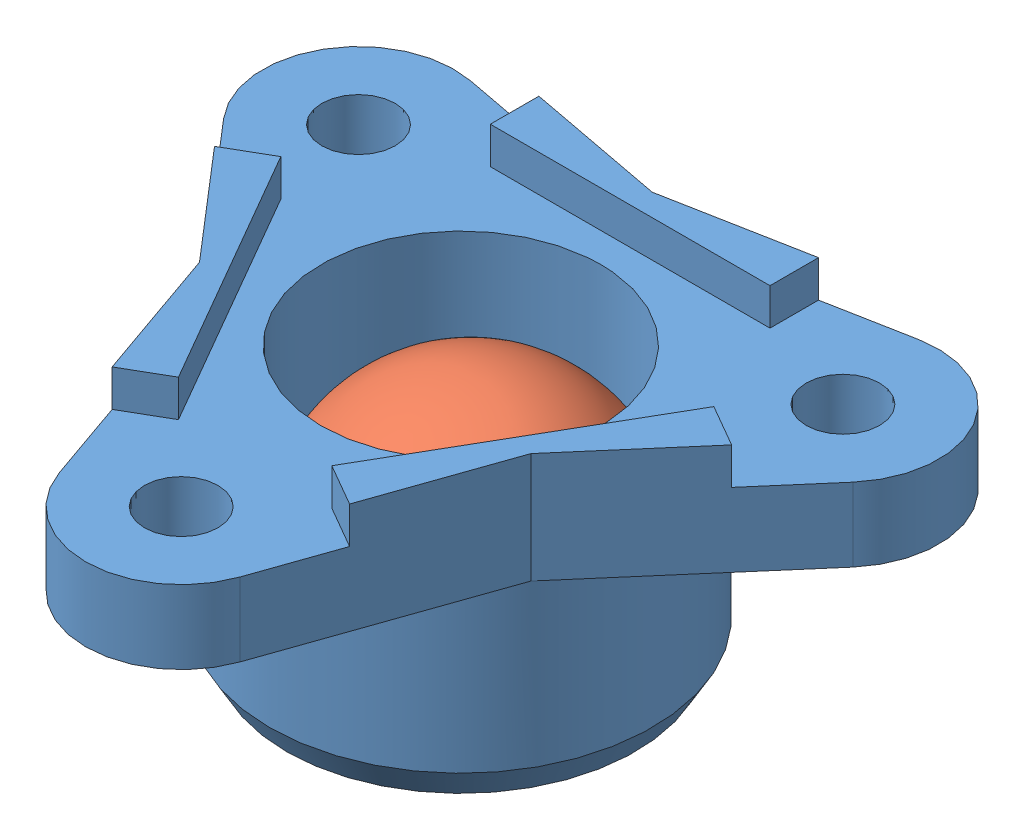
SolidWorks assembly CCastorAss, configuration Default. Lengths in mm.
Overall size (22.95 11.75 20.75).
2 component instances, 2 part files, 0 mates.
Components (placement in the parent):
- casterWheel_bottom_V2-2: CcasterWheel_bottom_V2 [Default] x (1 0 0) z (0 0 -1) size (22.95 10.25 20.75)
- casterWheel-1: CcasterWheel [Default] at (0.5512 -5.5 0.2177) size (10 10 10)
